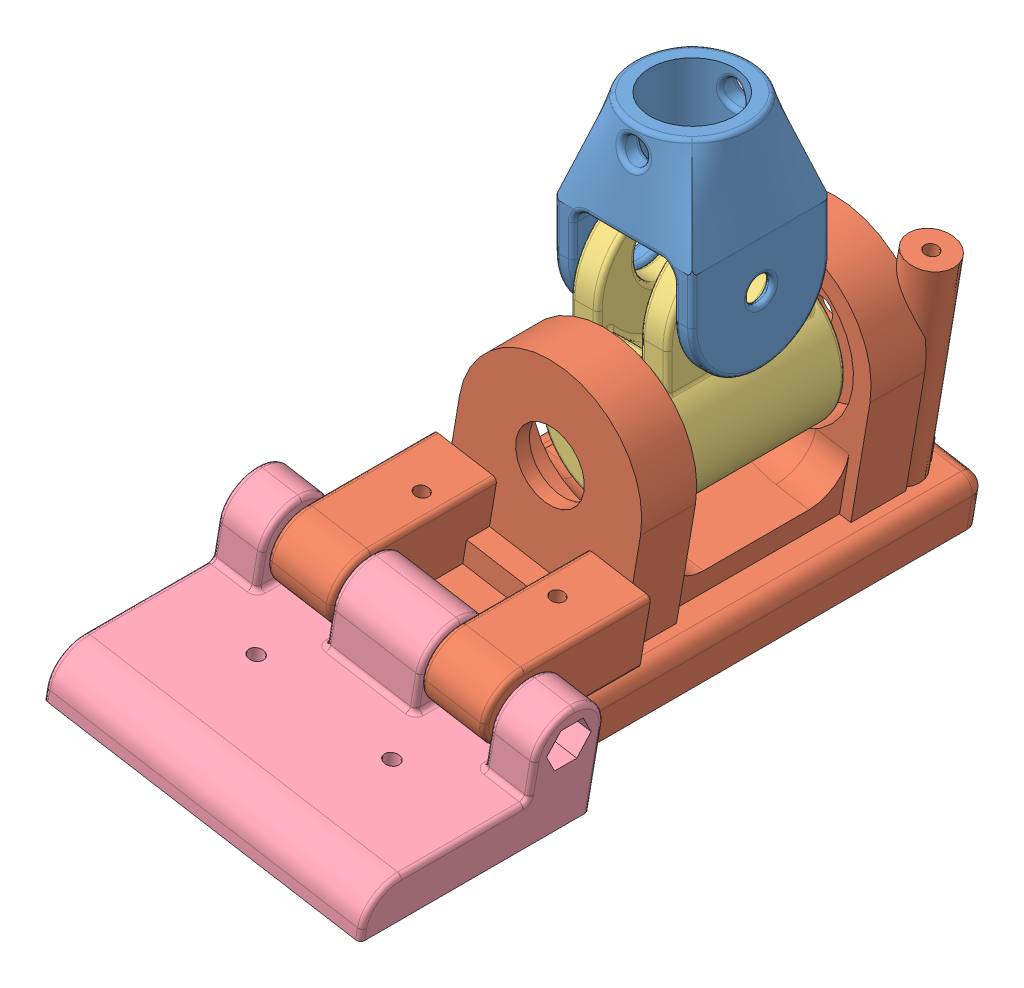
SolidWorks assembly footassem, configuration Default. Lengths in mm.
Overall size (73.26 96.03 145).
4 component instances, 4 part files, 6 mates.
Components (placement in the parent):
- ankle1_r-1: ankle1_r [Default] at (18.5562 22.4491 36.2186) size (30 45.21 30.45)
- foot-1: foot [Default] at (12.7467 -47.0654 57.2186) x (0 0 -1) z (0.986128 -0.165985 0) size (110 55 50)
- t-1: t [Default] at (18.5562 -12.5509 36.2186) x (-1 0 0) z (0 0 -1) size (30 50 37)
- toes-1: toes [Default] at (12.6623 -47.5672 112.2186) x (0 0 -1) z (0.986128 -0.165985 0) size (50 25.5 70)
Mates (geometry in assembly coordinates):
- Concentric2: concentric aligned: cylinder of foot-1 through (-9.0032 -25.6673 72.5118) axis (0.986128 -0.165985 0) radius 2.7; cylinder of toes-1 through (-18.8645 -24.0074 72.5118) axis (0.986128 -0.165985 0) radius 2.6
- Width1: width aligned: plane of toes-1 through (48.8366 -43.5154 90.0118) normal (0.986128 -0.165985 0); plane of toes-1 through (-20.1924 -31.8965 90.0118) normal (-0.986128 0.165985 0); plane of foot-1 through (40.5634 -26.3958 80.0118) normal (0.986128 -0.165985 0); plane of foot-1 through (-6.7707 -18.4286 80.0118) normal (-0.986128 0.165985 0)
- Concentric3: concentric anti-aligned: cylinder of ankle1_r-1 through (31.5562 12.4491 36.2186) axis (-1 0 0) radius 7.65; cylinder of t-1 through (3.5562 12.4491 36.2186) axis (1 0 0) radius 7.65
- Width2: width aligned: plane of ankle1_r-1 through (33.5562 -2.5509 36.2186) normal (1 0 0); plane of ankle1_r-1 through (3.5562 -2.5509 36.2186) normal (-1 0 0); plane of t-1 through (29.1562 22.4491 36.2186) normal (1 0 0); plane of t-1 through (7.9562 22.4491 36.2186) normal (-1 0 0)
- Concentric4: concentric anti-aligned: cylinder of foot-1 through (18.5562 -12.5509 -16.9882) axis (0 0 1) radius 16.15; cylinder of t-1 through (18.5562 -12.5509 54.7186) axis (0 0 -1) radius 15
- Width3: width aligned: plane of foot-1 through (12.7467 -47.0654 67.2186) normal (0 0 1); plane of foot-1 through (12.7467 -47.0654 5.2186) normal (0 0 -1); plane of t-1 through (18.5562 -12.5509 54.7186) normal (0 0 1); plane of t-1 through (18.5562 -12.5509 17.7186) normal (0 0 -1)
